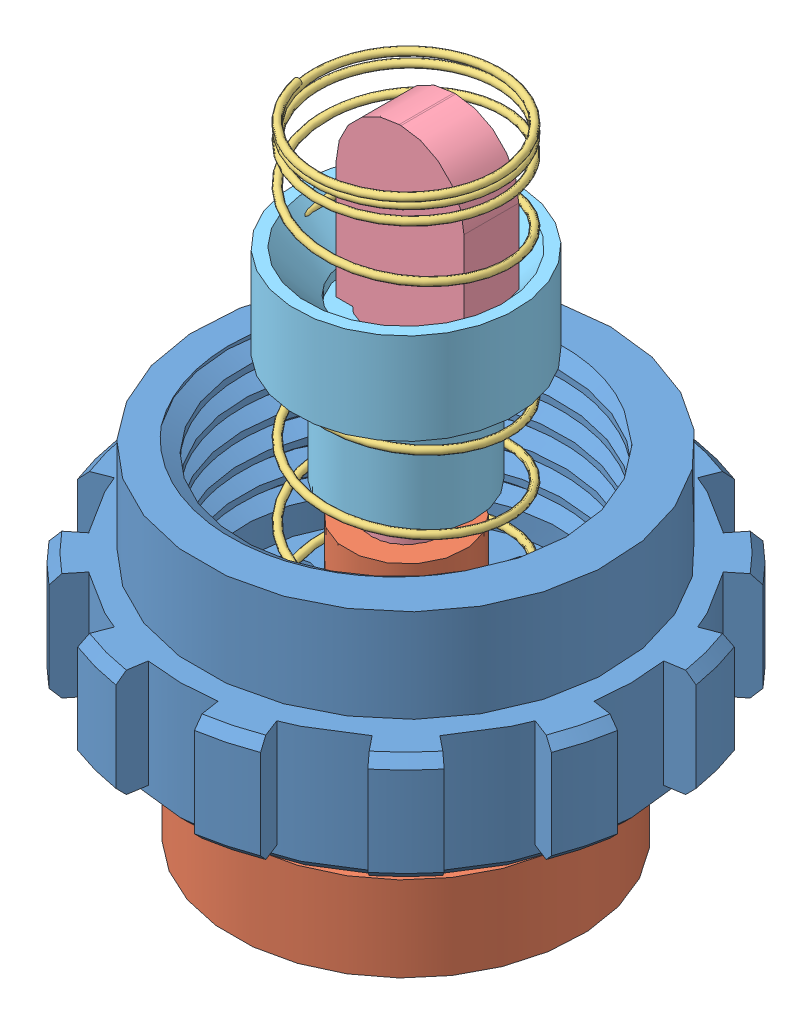
SolidWorks assembly Assem2, configuration Default. Lengths in mm.
Overall size (27.47 35.1 27.47).
5 component instances, 5 part files, 8 mates.
Components (placement in the parent):
- Pressure Relief Valve Body-1: Pressure Relief Valve Body [Default] at origin size (27.47 12.53 27.47)
- Pressure Relief Valve Pop_Up-1: Pressure Relief Valve Pop_Up [Default] at (0 -6.6 0) size (18.9 15.2 18.9)
- Pressure Relief Valve Spring-1: Pressure Relief Valve Spring [Default] at (0 2.3 0) size (10.65 25.8 10.87)
- Pressure Relief Valve Pin Center-1: Pressure Relief Valve Pin Center [Default] at (0 3.6 0) size (7.5 24.9 5.65)
- Pressure Relief Valve Seal-1: Pressure Relief Valve Seal [Default] at (0 10.4 0) x (0.927686 0 -0.373362) z (0.373362 0 0.927686) size (12 11 12)
Mates (geometry in assembly coordinates):
- Concentric1: concentric anti-aligned: cylinder of Pressure Relief Valve Body-1 through (0 -7.7 0) axis (0 1 0) radius 3.5; cylinder of Pressure Relief Valve Pop_Up-1 through (0 -6.6 0) axis (0 -1 0) radius 3.19
- Distance1: distance = 0 mm anti-aligned: plane of Pressure Relief Valve Pop_Up-1 through (5.25 0 0) normal (0 1 0); plane of Pressure Relief Valve Body-1 through (0 0 0) normal (0 -1 0)
- Coincident1: coincident aligned: plane of Pressure Relief Valve Body-1 through (8.75 2.3 0) normal (0 1 0); plane of Pressure Relief Valve Spring-1 through (0 2.3 0) normal (0 1 0)
- Concentric2: concentric aligned: cylinder of Pressure Relief Valve Pop_Up-1 through (0 -6.6 0) axis (0 -1 0) radius 1.9; line of Pressure Relief Valve Spring-1 through (100 0 52.3) axis (0 0 -1)
- Coincident2: coincident: plane of Pressure Relief Valve Pop_Up-1 through (1.9 3.6 0) normal (0 1 0); plane of Pressure Relief Valve Pin Center-1 through (0 3.6 0) normal (0 -1 0)
- Concentric3: concentric aligned: cylinder of Pressure Relief Valve Pop_Up-1 through (0 -6.6 0) axis (0 -1 0) radius 1.9; cylinder of Pressure Relief Valve Pin Center-1 through (0 3.6 0) axis (0 -1 0) radius 1.9
- Concentric4: concentric: cylinder of Pressure Relief Valve Pin Center-1 through (0 3.6 0) axis (0 -1 0) radius 1.9; cylinder of Pressure Relief Valve Seal-1 through (0 10.4 0) axis (0 -1 0) radius 3.8
- Distance2: distance = 0 mm: plane of Pressure Relief Valve Seal-1 through (3.015 18.6 -1.2134) normal (0 1 0); line of Pressure Relief Valve Pin Center-1 through (2.575 18.6 1.5) axis (0 0 -1)
